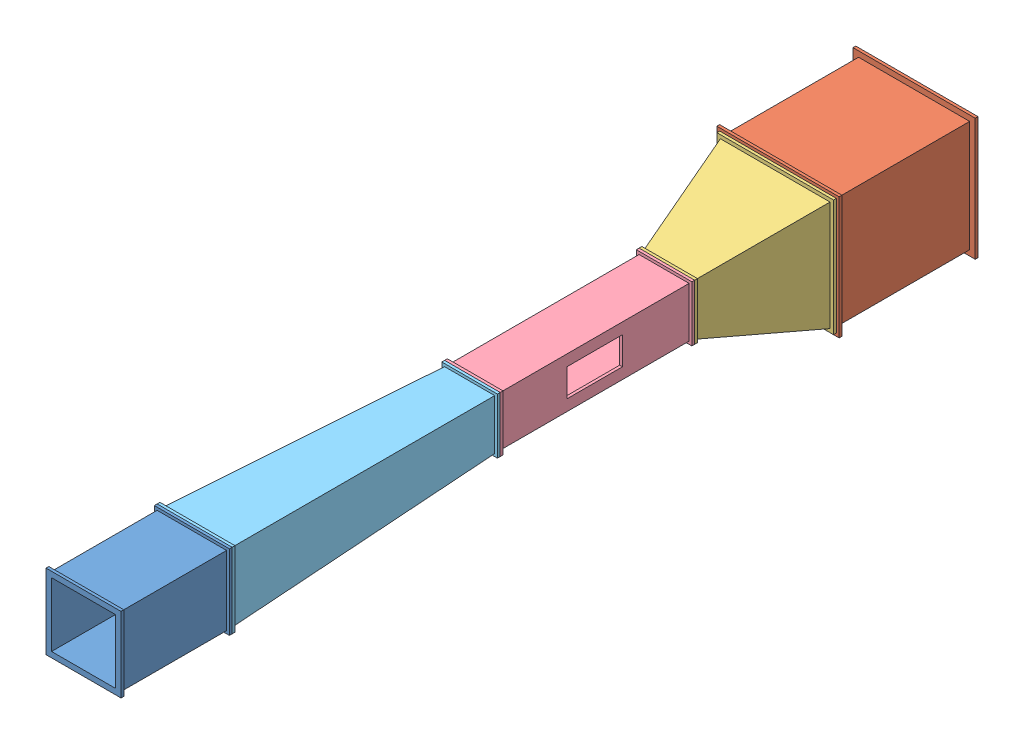
SolidWorks assembly Wind Tunnel, configuration Default. Lengths in mm.
Overall size (220 220 1500).
5 component instances, 5 part files, 11 mates.
Components (placement in the parent):
- Exit-1: Exit [Default] at (-177.3205 242.7116 1647.1248) size (135 135 200)
- inlet-1: inlet [Default] at (-177.3205 242.7116 347.1248) size (220 220 250)
- Nozzle-1: Nozzle [Default] at (-177.3205 242.7116 597.1248) size (210 210 200)
- Test Section-1: Test Section [Default] at (-177.3205 242.7116 797.1248) size (100 100 350)
- Diffuser-2: Diffuser [Default] at (-177.3205 242.7116 1147.1248) size (135 135 500)
Mates (geometry in assembly coordinates):
- Coincident2: coincident anti-aligned: plane of Nozzle-1 through (-177.3205 242.7116 797.1248) normal (0 0 1); plane of Test Section-1 through (-177.3205 242.7116 797.1248) normal (0 0 -1)
- Coincident3: coincident aligned: plane of Nozzle-1 through (-127.3205 192.7116 792.1248) normal (1 0 0); plane of Test Section-1 through (-127.3205 292.7116 802.1248) normal (1 0 0)
- Coincident4: coincident aligned: plane of Nozzle-1 through (-127.3205 292.7116 792.1248) normal (0 1 0); plane of Test Section-1 through (-227.3205 292.7116 802.1248) normal (0 1 0)
- Coincident16: coincident anti-aligned: line of inlet-1 through (-82.3205 147.7116 597.1248) axis (0 1 0); line of Nozzle-1 through (-82.3205 337.7116 597.1248) axis (0 -1 0)
- Coincident17: coincident anti-aligned: line of inlet-1 through (-82.3205 337.7116 597.1248) axis (-1 0 0); line of Nozzle-1 through (-272.3205 337.7116 597.1248) axis (1 0 0)
- Coincident18: coincident anti-aligned: plane of Test Section-1 through (-177.3205 242.7116 1147.1248) normal (0 0 1); plane of Diffuser-2 through (-177.3205 242.7116 1147.1248) normal (0 0 -1)
- Coincident19: coincident aligned: plane of Test Section-1 through (-127.3205 192.7116 1142.1248) normal (1 0 0); plane of Diffuser-2 through (-127.3205 292.7116 1152.1248) normal (1 0 0)
- Coincident20: coincident aligned: plane of Test Section-1 through (-227.3205 192.7116 1142.1248) normal (0 -1 0); plane of Diffuser-2 through (-127.3205 192.7116 1152.1248) normal (0 -1 0)
- Coincident21: coincident anti-aligned: plane of Exit-1 through (-177.3205 107.7116 1647.1248) normal (0 0 -1); plane of Diffuser-2 through (-177.3205 242.7116 1647.1248) normal (0 0 1)
- Coincident22: coincident aligned: plane of Exit-1 through (-109.8205 175.2116 1652.1248) normal (1 0 0); plane of Diffuser-2 through (-109.8205 242.7116 1642.1248) normal (1 0 0)
- Coincident23: coincident aligned: plane of Exit-1 through (-244.8205 175.2116 1652.1248) normal (0 1 0); plane of Diffuser-2 through (-177.3205 310.2116 1642.1248) normal (0 1 0)
